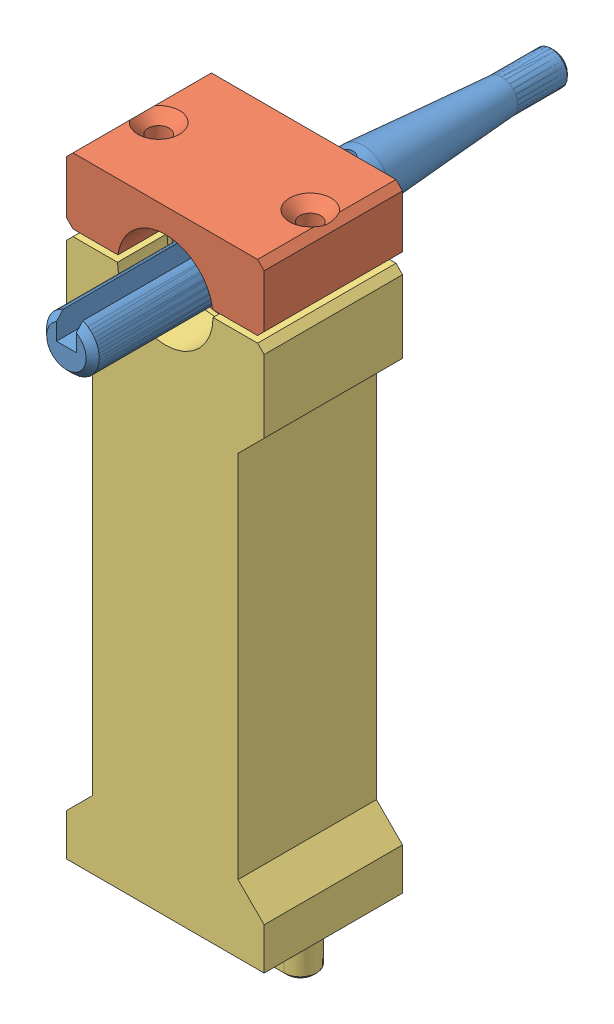
SolidWorks assembly Сборка1, configuration Default. Lengths in mm.
Overall size (30 100.57 74).
4 component instances, 4 part files, 7 mates.
Components (placement in the parent):
- front_axis-1: front_axis [Spur01] at (20.0213 44.4681 48.9019) size (12 11.81 74)
- front_axis_cover-1: front_axis_cover [Default] at (20.0213 44.5015 57.9019) size (30 10.31 21)
- front_axis_support-1: front_axis_support [По умолчанию] at (20.0213 44.4681 57.9019) size (30 89.27 21)
- Подшипник 1000088 ГОСТ 8338-75-2: Подшипник 1000088 ГОСТ 8338-75 [Подшипник 1000088 ГОСТ 8338-75] at (20.0213 44.4681 66.4019) x (0 0 1) z (-1 0 0) size (4 16 16)
Mates (geometry in assembly coordinates):
- Концентричный11: concentric aligned: cylinder of front_axis-1 through (20.0213 44.4681 93.9019) axis (0 0 1) radius 4; cylinder of Подшипник 1000088 ГОСТ 8338-75-2 through (20.0213 44.4681 66.4019) axis (0 0 1) radius 4
- Совпадение11: coincident anti-aligned: plane of front_axis-1 through (28.1814 44.4681 66.4019) normal (0 0 1); plane of Подшипник 1000088 ГОСТ 8338-75-2 through (20.0213 48.4681 66.4019) normal (0 0 -1)
- Концентричный2: concentric: cylinder of front_axis_support-1 through (20.0213 44.4681 59.9019) axis (0 0 -1) radius 8; cylinder of Подшипник 1000088 ГОСТ 8338-75-2 through (20.0213 44.4681 66.4019) axis (0 0 -1) radius 8
- Расстояние1: distance = 1 mm anti-aligned: plane of front_axis_support-1 through (12.0213 44.4681 65.4019) normal (0 0 1); plane of Подшипник 1000088 ГОСТ 8338-75-2 through (20.0213 44.4681 66.4019) normal (0 0 -1)
- Концентричный3: concentric: cylinder of front_axis_cover-1 through (31.5213 66.6304 68.4019) axis (0 1 0) radius 1.6; cylinder of front_axis_support-1 through (31.5213 44.4681 68.4019) axis (0 1 0) radius 1.25
- Концентричный4: concentric: cylinder of front_axis_cover-1 through (8.5213 66.6304 68.4019) axis (0 1 0) radius 1.6; cylinder of front_axis_support-1 through (8.5213 44.4681 68.4019) axis (0 1 0) radius 1.25
- Расстояние2: distance = 1 mm anti-aligned: plane of front_axis_support-1 through (5.0213 44.4681 78.9019) normal (0 1 0); plane of front_axis_cover-1 through (5.0213 45.4681 78.9019) normal (0 -1 0)
